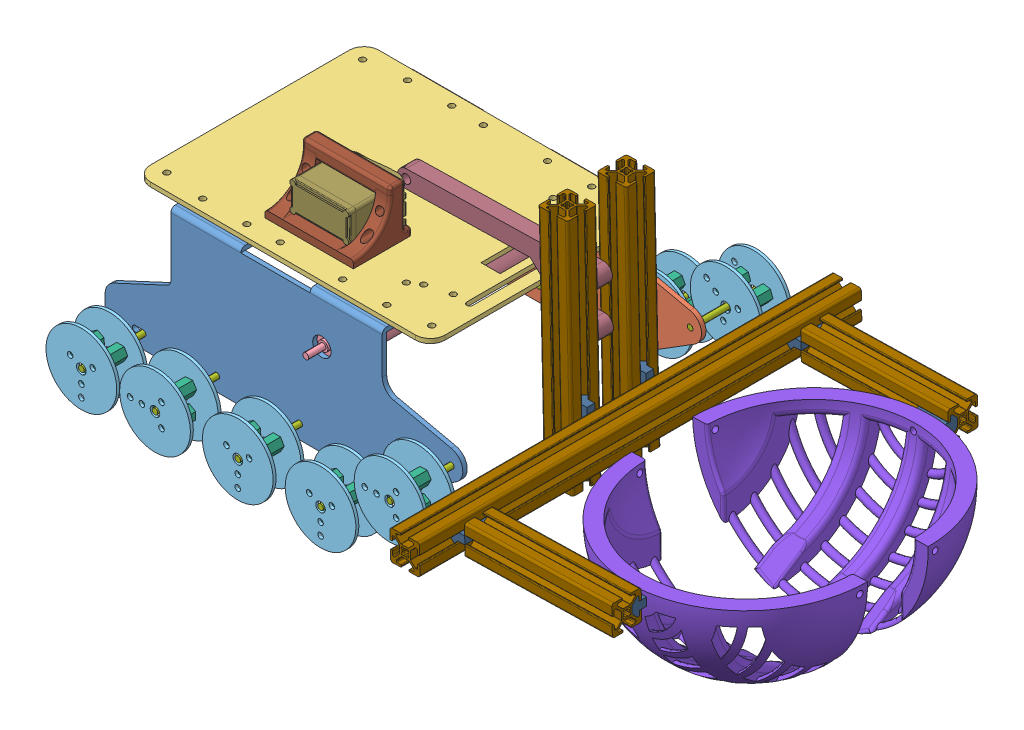
SolidWorks assembly Robot_with_Collector, configuration Default. Lengths in mm.
Overall size (463.67 199.97 300).
98 component instances, 13 part files, 13 mates.
Components (placement in the parent):
- Small_Robot_Assembly-1: Small_Robot_Assembly [Default] at (17.3939 -3.766 74.55) size (268.95 110.35 249.1)
  - Right_Side-1: Right_Side [Default] at (-96.7402 64.2453 5) size (242.92 93 16)
  - Left_Side-1: Left_Side [Default] at (-96.7402 64.2453 -157.1) size (242.92 93 16)
  - Top_Plate-1: Top_Plate [Default] at (74.3598 67.2453 -152.05) x (-1 0 0) z (0 0 -1) size (200 3 155)
  - Motor-1: Motor [Default] at (5.7598 36.4953 -64.35) x (0.998113 -0.061402 0) z (0 0 1) size (26.5 26.5 83.25)
  - Motor-2: Motor [Default] at (5.7598 36.4953 -84.75) x (-1 0 0) z (0 0 -1) size (26.5 26.5 83.25)
  - Wheel_Assembly-1: Wheel_Assembly [Default] at (93.7077 10.7426 -178.2) x (-0.641376 -0.767227 0) z (0.767227 -0.641376 0) size (48 45 48)
    - Wheel Face-1: Wheel Face [Default] at origin size (48 2 48)
    - Wheel Standoff-1: Wheel Standoff [Default] at (7.6643 2 4.425) x (-0.835985 0 0.548752) z (-0.548752 0 -0.835985) size (10 16.9 8.66)
    - Wheel Standoff-2: Wheel Standoff [Default] at (0 2 -8.85) size (10 16.9 8.66)
    - Wheel Standoff-3: Wheel Standoff [Default] at (-7.6643 2 4.425) size (10 16.9 8.66)
    - Wheel Face-2: Wheel Face [Default] at (0 18.9 0) size (48 2 48)
    - Wheel Axel-1: Wheel Axel [Default] at (0 -24.1 0) x (0.582426 0 0.812884) z (-0.812884 0 0.582426) size (3.75 45 3.75)
  - Wheel_Assembly-2: Wheel_Assembly [Default] at (93.7077 10.7426 29.1) x (0 1 0) z (1 0 0) size (48 45 48)
    - Wheel Face-1: Wheel Face [Default] at origin size (48 2 48)
    - Wheel Standoff-1: Wheel Standoff [Default] at (7.6643 2 4.425) x (-0.835985 0 0.548752) z (-0.548752 0 -0.835985) size (10 16.9 8.66)
    - Wheel Standoff-2: Wheel Standoff [Default] at (0 2 -8.85) size (10 16.9 8.66)
    - Wheel Standoff-3: Wheel Standoff [Default] at (-7.6643 2 4.425) size (10 16.9 8.66)
    - Wheel Face-2: Wheel Face [Default] at (0 18.9 0) size (48 2 48)
    - Wheel Axel-1: Wheel Axel [Default] at (0 -24.1 0) x (0.582426 0 0.812884) z (-0.812884 0 0.582426) size (3.75 45 3.75)
  - Wheel_Assembly-3: Wheel_Assembly [Default] at (46.8781 -16.1047 29.1) x (-1 0 0) z (0 1 0) size (48 45 48)
    - Wheel Face-1: Wheel Face [Default] at origin size (48 2 48)
    - Wheel Standoff-1: Wheel Standoff [Default] at (7.6643 2 4.425) x (-0.835985 0 0.548752) z (-0.548752 0 -0.835985) size (10 16.9 8.66)
    - Wheel Standoff-2: Wheel Standoff [Default] at (0 2 -8.85) size (10 16.9 8.66)
    - Wheel Standoff-3: Wheel Standoff [Default] at (-7.6643 2 4.425) size (10 16.9 8.66)
    - Wheel Face-2: Wheel Face [Default] at (0 18.9 0) size (48 2 48)
    - Wheel Axel-1: Wheel Axel [Default] at (0 -24.1 0) x (0.582426 0 0.812884) z (-0.812884 0 0.582426) size (3.75 45 3.75)
  - Wheel_Assembly-4: Wheel_Assembly [Default] at (-9.3219 -16.1047 29.1) x (-1 0 0) z (0 1 0) size (48 45 48)
    - Wheel Face-1: Wheel Face [Default] at origin size (48 2 48)
    - Wheel Standoff-1: Wheel Standoff [Default] at (7.6643 2 4.425) x (-0.835985 0 0.548752) z (-0.548752 0 -0.835985) size (10 16.9 8.66)
    - Wheel Standoff-2: Wheel Standoff [Default] at (0 2 -8.85) size (10 16.9 8.66)
    - Wheel Standoff-3: Wheel Standoff [Default] at (-7.6643 2 4.425) size (10 16.9 8.66)
    - Wheel Face-2: Wheel Face [Default] at (0 18.9 0) size (48 2 48)
    - Wheel Axel-1: Wheel Axel [Default] at (0 -24.1 0) x (0.582426 0 0.812884) z (-0.812884 0 0.582426) size (3.75 45 3.75)
  - Wheel_Assembly-5: Wheel_Assembly [Default] at (-65.5219 -16.1047 29.1) x (0 1 0) z (1 0 0) size (48 45 48)
    - Wheel Face-1: Wheel Face [Default] at origin size (48 2 48)
    - Wheel Standoff-1: Wheel Standoff [Default] at (7.6643 2 4.425) x (-0.835985 0 0.548752) z (-0.548752 0 -0.835985) size (10 16.9 8.66)
    - Wheel Standoff-2: Wheel Standoff [Default] at (0 2 -8.85) size (10 16.9 8.66)
    - Wheel Standoff-3: Wheel Standoff [Default] at (-7.6643 2 4.425) size (10 16.9 8.66)
    - Wheel Face-2: Wheel Face [Default] at (0 18.9 0) size (48 2 48)
    - Wheel Axel-1: Wheel Axel [Default] at (0 -24.1 0) x (0.582426 0 0.812884) z (-0.812884 0 0.582426) size (3.75 45 3.75)
  - Wheel_Assembly-6: Wheel_Assembly [Default] at (-115.5219 -16.1047 29.1) x (-1 0 0) z (0 1 0) size (48 45 48)
    - Wheel Face-1: Wheel Face [Default] at origin size (48 2 48)
    - Wheel Standoff-1: Wheel Standoff [Default] at (7.6643 2 4.425) x (-0.835985 0 0.548752) z (-0.548752 0 -0.835985) size (10 16.9 8.66)
    - Wheel Standoff-2: Wheel Standoff [Default] at (0 2 -8.85) size (10 16.9 8.66)
    - Wheel Standoff-3: Wheel Standoff [Default] at (-7.6643 2 4.425) size (10 16.9 8.66)
    - Wheel Face-2: Wheel Face [Default] at (0 18.9 0) size (48 2 48)
    - Wheel Axel-1: Wheel Axel [Default] at (0 -24.1 0) x (0.582426 0 0.812884) z (-0.812884 0 0.582426) size (3.75 45 3.75)
  - Wheel_Assembly-8: Wheel_Assembly [Default] at (46.8781 -16.1047 -178.2) x (0 1 0) z (-1 0 0) size (48 45 48)
    - Wheel Face-1: Wheel Face [Default] at origin size (48 2 48)
    - Wheel Standoff-1: Wheel Standoff [Default] at (7.6643 2 4.425) x (-0.835985 0 0.548752) z (-0.548752 0 -0.835985) size (10 16.9 8.66)
    - Wheel Standoff-2: Wheel Standoff [Default] at (0 2 -8.85) size (10 16.9 8.66)
    - Wheel Standoff-3: Wheel Standoff [Default] at (-7.6643 2 4.425) size (10 16.9 8.66)
    - Wheel Face-2: Wheel Face [Default] at (0 18.9 0) size (48 2 48)
    - Wheel Axel-1: Wheel Axel [Default] at (0 -24.1 0) x (0.582426 0 0.812884) z (-0.812884 0 0.582426) size (3.75 45 3.75)
  - Wheel_Assembly-9: Wheel_Assembly [Default] at (-9.3219 -16.1047 -178.2) x (0 1 0) z (-1 0 0) size (48 45 48)
    - Wheel Face-1: Wheel Face [Default] at origin size (48 2 48)
    - Wheel Standoff-1: Wheel Standoff [Default] at (7.6643 2 4.425) x (-0.835985 0 0.548752) z (-0.548752 0 -0.835985) size (10 16.9 8.66)
    - Wheel Standoff-2: Wheel Standoff [Default] at (0 2 -8.85) size (10 16.9 8.66)
    - Wheel Standoff-3: Wheel Standoff [Default] at (-7.6643 2 4.425) size (10 16.9 8.66)
    - Wheel Face-2: Wheel Face [Default] at (0 18.9 0) size (48 2 48)
    - Wheel Axel-1: Wheel Axel [Default] at (0 -24.1 0) x (0.582426 0 0.812884) z (-0.812884 0 0.582426) size (3.75 45 3.75)
  - Wheel_Assembly-10: Wheel_Assembly [Default] at (-65.5219 -16.1047 -178.2) x (0 1 0) z (-1 0 0) size (48 45 48)
    - Wheel Face-1: Wheel Face [Default] at origin size (48 2 48)
    - Wheel Standoff-1: Wheel Standoff [Default] at (7.6643 2 4.425) x (-0.835985 0 0.548752) z (-0.548752 0 -0.835985) size (10 16.9 8.66)
    - Wheel Standoff-2: Wheel Standoff [Default] at (0 2 -8.85) size (10 16.9 8.66)
    - Wheel Standoff-3: Wheel Standoff [Default] at (-7.6643 2 4.425) size (10 16.9 8.66)
    - Wheel Face-2: Wheel Face [Default] at (0 18.9 0) size (48 2 48)
    - Wheel Axel-1: Wheel Axel [Default] at (0 -24.1 0) x (0.582426 0 0.812884) z (-0.812884 0 0.582426) size (3.75 45 3.75)
  - Wheel_Assembly-11: Wheel_Assembly [Default] at (-115.5219 -16.1047 -178.2) x (0 1 0) z (-1 0 0) size (48 45 48)
    - Wheel Face-1: Wheel Face [Default] at origin size (48 2 48)
    - Wheel Standoff-1: Wheel Standoff [Default] at (7.6643 2 4.425) x (-0.835985 0 0.548752) z (-0.548752 0 -0.835985) size (10 16.9 8.66)
    - Wheel Standoff-2: Wheel Standoff [Default] at (0 2 -8.85) size (10 16.9 8.66)
    - Wheel Standoff-3: Wheel Standoff [Default] at (-7.6643 2 4.425) size (10 16.9 8.66)
    - Wheel Face-2: Wheel Face [Default] at (0 18.9 0) size (48 2 48)
    - Wheel Axel-1: Wheel Axel [Default] at (0 -24.1 0) x (0.582426 0 0.812884) z (-0.812884 0 0.582426) size (3.75 45 3.75)
- Collector_Assembly-1: Collector_Assembly [Default] at (229.4416 92.8228 -17.1089) x (0 0 1) z (-0.022715 0.999742 0) size (300 220.52 195.01)
  - Collector Hand-1: Collector Hand [Default] at (43.9345 -53.2163 -71.1291) size (80.24 160 80)
  - Collector Hand-2: Collector Hand [Default] at (2.6754 106.7837 -71.1291) x (-1 0 0) z (0 0 1) size (80.24 160 80)
  - 2020_aluminum_bar-1: 2020_aluminum_bar [20-2020-300mm] at (-125.4411 -76.722 -76.1244) x (0 0 -1) z (1 0 0) size (20 20 300)
  - 2020_aluminum_bar_side_connector-1: 2020_aluminum_bar_side_connector [Default] at (-80.8303 -73.0635 -76.1268) x (0 -1 0) z (0 0 -1) size (9.85 20 11.99)
  - 2020_aluminum_bar-2: 2020_aluminum_bar [20-2020-100mm] at (-90.8303 -63.2163 -76.1268) x (0 0 1) z (0 1 0) size (20 20 100)
  - 2020_aluminum_bar_side_connector-2: 2020_aluminum_bar_side_connector [Default] at (-87.1717 36.7837 -76.1291) x (-1 0 0) z (0 0 1) size (9.85 20 11.99)
  - 2020_aluminum_bar_side_connector-3: 2020_aluminum_bar_side_connector [Default] at (147.4402 -73.0635 -76.1268) x (0 -1 0) z (0 0 -1) size (9.85 20 11.99)
  - 2020_aluminum_bar-3: 2020_aluminum_bar [20-2020-100mm] at (137.4402 36.7837 -76.1268) x (-1 0 0) z (0 -1 0) size (20 20 100)
  - 2020_aluminum_bar_side_connector-4: 2020_aluminum_bar_side_connector [Default] at (133.7816 16.7837 -76.1291) size (9.85 20 11.99)
  - 2020_aluminum_bar-4: 2020_aluminum_bar [ 20-2020-160mm] at (-5.4411 -103.7334 -116.1268) size (20 20 160)
  - 2020_aluminum_bar_side_connector-5: 2020_aluminum_bar_side_connector [Default] at (4.5613 -80.3806 -76.1268) x (0 1 0) z (0 0 1) size (9.85 20 11.99)
  - 2020_aluminum_bar_side_connector-6: 2020_aluminum_bar_side_connector [Default] at (-5.4387 -100.0748 -86.1268) x (0 -1 0) z (-1 0 0) size (9.85 20 11.99)
  - 2020_aluminum_bar-5: 2020_aluminum_bar [ 20-2020-160mm] at (34.5589 -103.7334 -116.1221) size (20 20 160)
  - 2020_aluminum_bar_side_connector-7: 2020_aluminum_bar_side_connector [Default] at (44.5613 -80.3806 -76.1221) x (0 1 0) z (0 0 1) size (9.85 20 11.99)
  - 2020_aluminum_bar_side_connector-8: 2020_aluminum_bar_side_connector [Default] at (34.5613 -100.0748 -86.1221) x (0 -1 0) z (-1 0 0) size (9.85 20 11.99)
- Servo_Assembly-2: Servo_Assembly [Default] at (21.7537 66.4793 19.75) x (-1 0 0) z (0 0 -1) size (60 35 52.3)
  - 20kg_Servo_Holder-1: 20kg_Servo_Holder [Default] at origin size (60 35 40)
  - Servo 20kg-1: Servo 20kg [Default] at (29.8 15.05 -33.35) x (-1 0 0) z (0 1 0) size (55.1 45.65 20.12)
- 2020_aluminum_bar_side_connector-1: 2020_aluminum_bar_side_connector [Default] at (126.0989 74.3486 13.7914) x (0 0 1) z (-0.999742 -0.022715 0) size (9.85 20 11.99)
- Collector Arm-2: Collector Arm [Default] at (1.9037 81.5293 3.9443) x (-0.999742 -0.022715 0) z (0.022715 -0.999742 0) size (136 10 42)
- 2020_aluminum_bar_side_connector-2: 2020_aluminum_bar_side_connector [Default] at (126.7803 44.3563 13.7914) x (0 0 1) z (-0.999742 -0.022715 0) size (9.85 20 11.99)
Mates (geometry in assembly coordinates):
- Distance3: distance = 50 mm aligned: plane of Small_Robot_Assembly-1/Left_Side-1 through (-83.724 20.4793 -82.55) normal (0 0 -1); plane of Collector_Assembly-1/2020_aluminum_bar-4 through (116.2392 134.1353 -32.55) normal (0 0 -1)
- Coincident3: coincident anti-aligned: plane of Small_Robot_Assembly-1/Top_Plate-1 through (91.7537 66.4793 -77.5) normal (0 1 0); plane of Servo_Assembly-2/20kg_Servo_Holder-1 through (21.7537 66.4793 19.75) normal (0 -1 0)
- Coincident4: coincident aligned: plane of Collector_Assembly-1/2020_aluminum_bar-5 through (116.2391 134.14 7.45) normal (0 0 -1); plane of Servo_Assembly-2/Servo 20kg-1 through (1.9037 81.5293 7.45) normal (0 0 -1)
- Coincident7: coincident: point of Servo_Assembly-2/20kg_Servo_Holder-1
- Coincident11: coincident anti-aligned: plane of Collector_Assembly-1/2020_aluminum_bar-5 through (127.1262 134.3874 13.7914) normal (0 0 -1); plane of 2020_aluminum_bar_side_connector-1 through (128.0339 94.3977 13.7914) normal (0 0 1)
- Coincident12: coincident anti-aligned: plane of Collector_Assembly-1/2020_aluminum_bar-5 through (130.5824 134.4659 10.5447) normal (-0.706924 -0.016062 -0.707107); plane of 2020_aluminum_bar_side_connector-1 through (131.4908 94.4762 10.5449) normal (0.706924 0.016062 0.707107)
- Distance6: distance = 40 mm aligned: plane of 2020_aluminum_bar_side_connector-1 through (131.1303 94.468 9.4543) normal (-0.022715 0.999742 0); plane of Collector_Assembly-1/2020_aluminum_bar-5 through (127.8744 134.4044 26.4594) normal (-0.022715 0.999742 0)
- Concentric3: concentric aligned: cylinder of Servo_Assembly-2/Servo 20kg-1 through (1.9037 81.5293 7.45) axis (0 0 1) radius 1; cylinder of Collector Arm-2 through (1.9037 81.5293 -6.0557) axis (0 0 1) radius 3
- Concentric4: concentric anti-aligned: cylinder of 2020_aluminum_bar_side_connector-1 through (125.8717 84.346 9.9443) axis (0 0 -1) radius 2.1; cylinder of Collector Arm-2 through (125.8717 84.346 -6.0557) axis (0 0 1) radius 1.5
- Coincident15: coincident anti-aligned: plane of 2020_aluminum_bar_side_connector-1 through (123.0152 94.2836 3.9443) normal (0 0 -1); plane of Collector Arm-2 through (1.9037 81.5293 3.9443) normal (0 0 1)
- Coincident16: coincident anti-aligned: plane of Collector_Assembly-1/2020_aluminum_bar-5 through (130.5824 134.4659 10.5447) normal (-0.706924 -0.016062 -0.707107); plane of 2020_aluminum_bar_side_connector-2 through (132.1723 64.484 10.5449) normal (0.706924 0.016062 0.707107)
- Coincident17: coincident anti-aligned: plane of Collector_Assembly-1/2020_aluminum_bar-5 through (127.1262 134.3874 13.7914) normal (0 0 -1); plane of 2020_aluminum_bar_side_connector-2 through (128.7154 64.4054 13.7914) normal (0 0 1)
- Concentric5: concentric aligned: cylinder of Collector Arm-2 through (126.5532 54.3537 58.8624) axis (0 0 -1) radius 1.5; cylinder of 2020_aluminum_bar_side_connector-2 through (126.5532 54.3537 9.9443) axis (0 0 -1) radius 2.1
